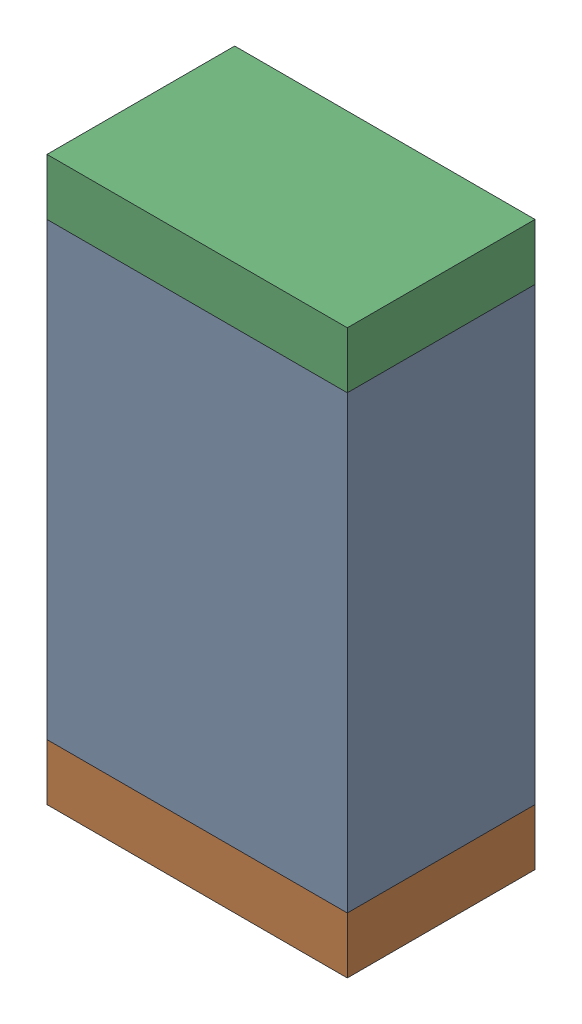
SolidWorks assembly R65, configuration Default. Lengths in mm.
Overall size (0.8 1.5 0.5).
6 component instances, 2 part files, 0 mates.
Components (placement in the parent):
- 810156976-1: 810156976 [Default] at (110 73.75 0) size (0.8 1.2 0.5)
  - Extruded_6-1: Extruded_6 [Default] at origin size (0.8 1.2 0.5)
- 810156592-1: 810156592 [Default] at (110 73.075 0) size (0.8 0.15 0.5)
  - Extruded_7-1: Extruded_7 [Default] at origin size (0.8 0.15 0.5)
- 810156592-2: 810156592 [Default] at (110 74.425 0) size (0.8 0.15 0.5)
  - Extruded_7-1: Extruded_7 [Default] at origin size (0.8 0.15 0.5)
